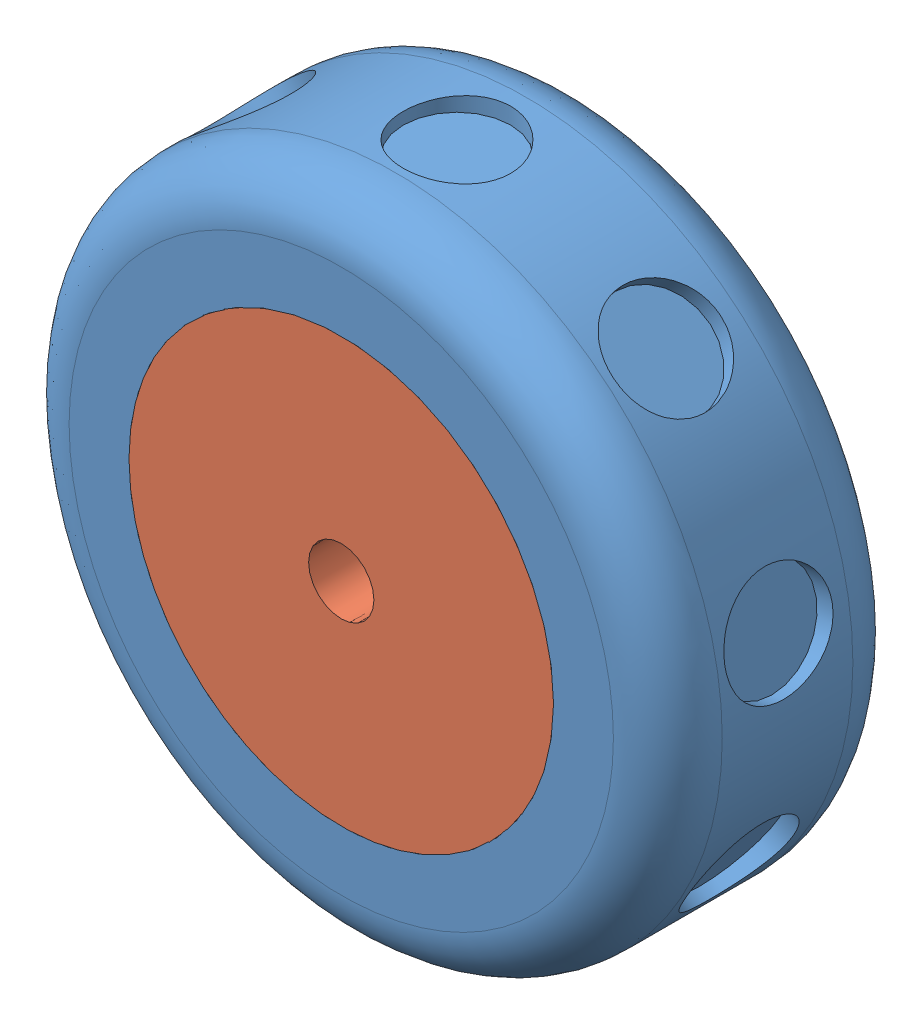
SolidWorks assembly Assem1, configuration Default. Lengths in mm.
Overall size (60 60 22).
2 component instances, 2 part files, 2 mates.
Components (placement in the parent):
- Wheel_External-1: Wheel_External [Default] at (-0.9064 32.1198 46.8024) size (60 60 22)
- Wheel_Ring-1: Wheel_Ring [Default] at (-0.9064 32.1198 57.8024) size (39 39 22)
Mates (geometry in assembly coordinates):
- Coincident4: coincident aligned: plane of Wheel_External-1 through (-0.9064 32.1198 46.8024) normal (0 0 -1); plane of Wheel_Ring-1 through (-0.9064 32.1198 46.8024) normal (0 0 -1)
- Coincident5: coincident aligned: plane of Wheel_External-1 through (-0.9064 32.1198 68.8024) normal (0 0 1); plane of Wheel_Ring-1 through (-0.9064 32.1198 68.8024) normal (0 0 1)
